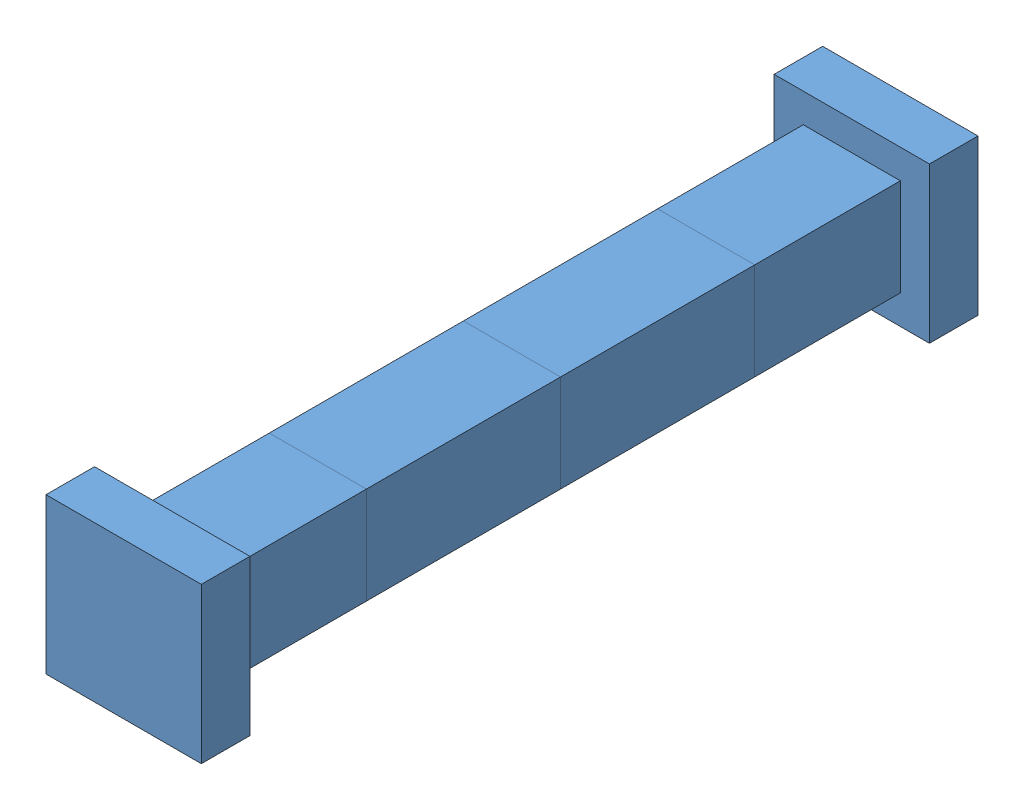
SolidWorks assembly Assemblage1, configuration Défaut. Lengths in mm.
Overall size (16 19.54 80).
4 component instances, 1 part files, 0 mates.
Components (placement in the parent):
- Pièce1-1: Pièce1 [Droite] at (-180.5637 6.5357 -10) size (16 16 20)
- Pièce1-2: Pièce1 [Défaut] at (-180.5637 6.5357 10) size (10 10 20)
- Pièce1-3: Pièce1 [Défaut] at (-180.5637 6.5357 30) size (10 10 20)
- Pièce1-4: Pièce1 [Gauche] at (-180.5637 6.5357 50) size (16 16 20)
